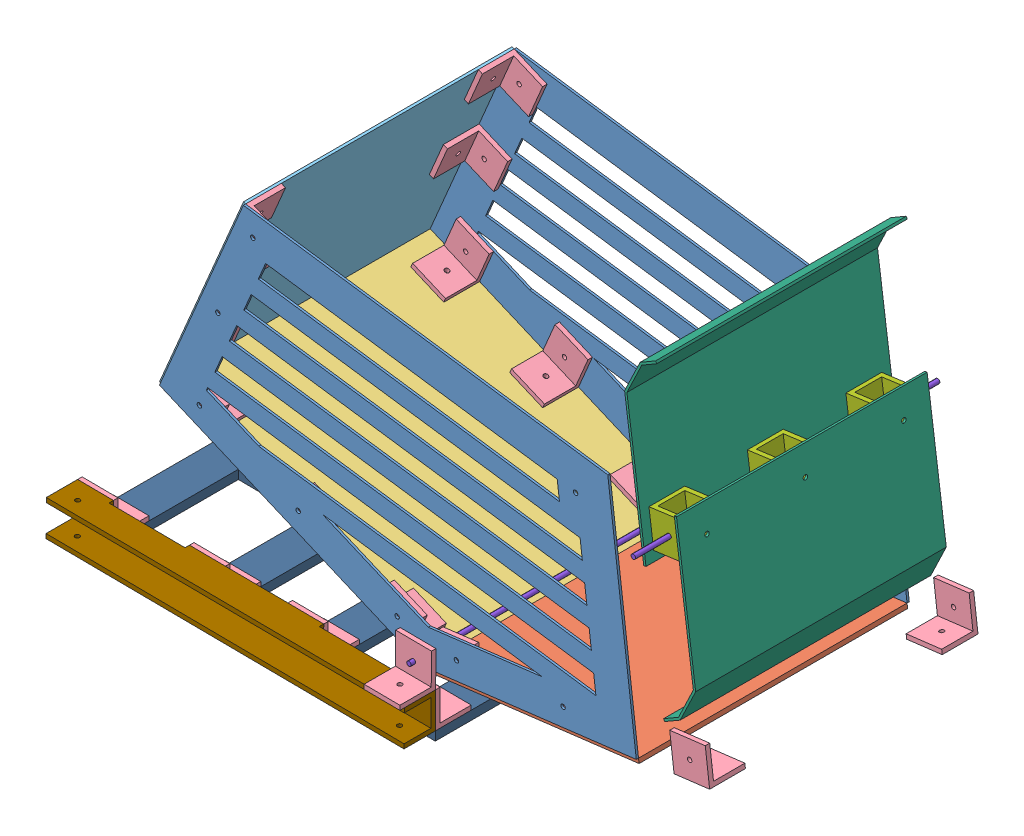
SolidWorks assembly total assem, configuration Default. Lengths in mm.
Overall size (442.28 299.16 254).
42 component instances, 11 part files, 72 mates.
Components (placement in the parent):
- 파트1-1: 파트1 [기본] at (16.2498 143.7805 409.1887) x (0.992546 0.121869 0) z (0 0 1) size (328.38 233.58 1.59)
- 파트1-2: 파트1 [기본] at (16.2498 143.7805 217.1012) x (0.992546 0.121869 0) z (0 0 1) size (328.38 233.58 1.59)
- 파트2-1: 파트2 [Default] at (117.4795 153.011 313.9387) x (0.992546 0.121869 0) z (0 0 1) size (152.4 3.17 190.5)
- 파트3-1: 파트3 [Default] at (-77.2734 183.4787 307.5887) x (-0.920505 0.390731 0) z (-0.390731 -0.920505 0) size (203.2 190.5 1.59)
- 파트5-2: 파트5 [Default] at (205.2455 166.9862 231.3887) x (0.992546 0.121869 0) z (-0.121869 0.992546 0) size (25.4 25.4 25.4)
- 파트5-3: 파트5 [Default] at (39.9128 159.4813 409.1887) x (0.992546 0.121869 0) z (0 0 -1) size (25.4 25.4 25.4)
- 파트5-5: 파트5 [Default] at (203.7942 179.5034 409.1887) x (0.992546 0.121869 0) z (0 0 -1) size (25.4 25.4 25.4)
- 파트5-6: 파트5 [Default] at (115.5448 168.7677 409.1887) x (0.992546 0.121869 0) z (0 0 -1) size (25.4 25.4 25.4)
- 파트5-7: 파트5 [Default] at (-2.1687 165.3954 409.1887) x (0.920505 -0.390731 0) z (0 0 -1) size (25.4 25.4 25.4)
- 파트5-8: 파트5 [Default] at (-72.3112 195.1691 409.1887) x (0.920505 -0.390731 0) z (0 0 -1) size (25.4 25.4 25.4)
- 파트5-10: 파트5 [Default] at (-72.3112 195.1691 218.6887) x (-0.920505 0.390731 0) z (0 0 1) size (25.4 25.4 25.4)
- 파트5-11: 파트5 [Default] at (-2.1687 165.3954 218.6887) x (-0.920505 0.390731 0) z (0 0 1) size (25.4 25.4 25.4)
- 파트5-12: 파트5 [Default] at (-142.4536 224.9429 218.6887) x (-0.920505 0.390731 0) z (0 0 1) size (25.4 25.4 25.4)
- 파트5-14: 파트5 [Default] at (39.9128 159.4813 218.6887) x (-0.992546 -0.121869 0) z (0 0 1) size (25.4 25.4 25.4)
- 파트5-15: 파트5 [Default] at (115.5448 168.7677 218.6887) x (-0.992546 -0.121869 0) z (0 0 1) size (25.4 25.4 25.4)
- 파트5-16: 파트5 [Default] at (-104.5212 346.8093 409.1887) x (-0.390731 -0.920505 0) z (0 0 -1) size (25.4 25.4 25.4)
- 파트5-17: 파트5 [Default] at (-142.4536 224.9429 409.1887) x (0.920505 -0.390731 0) z (0 0 -1) size (25.4 25.4 25.4)
- 파트5-18: 파트5 [Default] at (-129.3326 288.3572 409.1887) x (-0.390731 -0.920505 0) z (0 0 -1) size (25.4 25.4 25.4)
- 파트4-2: 파트4 [Default] at (-142.4843 293.9398 313.9387) x (-0.390731 -0.920505 0) z (0 0 1) size (152.4 1.59 190.5)
- 파트5-19: 파트5 [Default] at (-116.2116 351.7715 231.3887) x (-0.390731 -0.920505 0) z (0.920505 -0.390731 0) size (25.4 25.4 25.4)
- 파트5-20: 파트5 [Default] at (-141.023 293.3195 231.3887) x (-0.390731 -0.920505 0) z (0.920505 -0.390731 0) size (25.4 25.4 25.4)
- roller1-1: roller1 [Default] at (188.2429 345.4081 402.8387) x (0.991001 0.133852 0) z (0 0 -1) size (26.29 127.67 177.8)
- roller2-1: roller2 [Default] at (174.7933 309.5298 244.0887) x (0 0 1) z (0.991001 0.133852 0) size (25.4 25.4 25.4)
- roller3-1: roller3 [Default] at (17.3478 151.5925 205.9887) size (3.17 3.17 215.9)
- roller2-2: roller2 [Default] at (174.7933 309.5298 313.9387) x (0 0 1) z (0.991001 0.133852 0) size (25.4 25.4 25.4)
- roller2-5: roller2 [Default] at (174.7933 309.5298 383.7887) x (-0.991001 -0.133852 0) z (0 0 1) size (25.4 25.4 25.4)
- roller3-2: roller3 [Default] at (176.4933 296.9441 205.9887) size (3.17 3.17 215.9)
- LDO-2: LDO [Default] at (176.4933 296.9441 160.6199) x (0.973582 -0.228337 0) z (-0.228337 -0.973582 0) size (23.81 56.36 23.81) (hidden)
- roller1-2: roller1 [Default] at (164.7436 248.48 402.8387) x (-0.991001 -0.133852 0) z (0 0 -1) size (26.29 127.67 177.8)
- 파트5-21: 파트5 [Default] at (-62.2459 126.8861 212.3387) x (-0.999962 0.008727 0) z (0 0 1) size (25.4 25.4 25.4)
- 파트5-22: 파트5 [Default] at (17.3478 151.5925 415.5387) x (-0.999962 0.008727 0) z (0 0 1) size (25.4 25.4 25.4)
- 파트5-23: 파트5 [Default] at (-211.4652 128.1883 415.5387) x (0.999962 -0.008727 0) z (0 0 -1) size (25.4 25.4 25.4)
- 파트5-24: 파트5 [Default] at (17.1261 126.1935 212.3387) x (-0.999962 0.008727 0) z (0 0 1) size (25.4 25.4 25.4)
- 파트5-25: 파트5 [Default] at (-132.0932 127.4957 415.5387) x (0.999962 -0.008727 0) z (0 0 -1) size (25.4 25.4 25.4)
- 파트5-26: 파트5 [Default] at (-211.4652 128.1883 212.3387) x (-0.999962 0.008727 0) z (0 0 1) size (25.4 25.4 25.4)
- 파트7-1: 파트7 [Default] at (-224.1647 128.2992 201.2262) x (0 0 -1) z (0.999962 -0.008727 0) size (22.23 25.4 254)
- 파트6-1: 파트6 [Default] at (-97.3358 108.1416 313.9387) x (0 0 -1) z (0.008727 0.999962 0) size (203.2 254 6.35)
- 파트5-27: 파트5 [Default] at (-132.0932 127.4957 212.3387) x (-0.999962 0.008727 0) z (0 0 1) size (25.4 25.4 25.4)
- 파트7-2: 파트7 [Default] at (29.8256 126.0826 426.6512) x (0 0 1) z (-0.999962 0.008727 0) size (22.23 25.4 254)
- 파트5-28: 파트5 [Default] at (17.1261 126.1935 415.5387) x (0.999962 -0.008727 0) z (0 0 -1) size (25.4 25.4 25.4)
- 파트5-29: 파트5 [Default] at (-62.2459 126.8861 415.5387) x (0.999962 -0.008727 0) z (0 0 -1) size (25.4 25.4 25.4)
- 파트5-30: 파트5 [Default] at (17.3478 151.5925 212.3387) x (0.999962 -0.008727 0) z (0 0 -1) size (25.4 25.4 25.4)
Mates (geometry in assembly coordinates):
- 일치42: coincident aligned: circle of 파트3-1; circle of 파트5-10
- 일치43: coincident aligned: circle of 파트3-1; circle of 파트5-12
- 일치45: coincident aligned: circle of 파트4-2; circle of 파트5-20
- 일치46: coincident aligned: circle of 파트4-2; circle of 파트5-19
- 일치47: coincident anti-aligned: circle of 파트1-2; circle of 파트5-19
- 일치52: coincident aligned: cylinder of 파트1-2 through (-129.3326 288.3572 218.6887) axis (0 0 -1) radius 1.5875; circle of 파트5-20
- 일치57: coincident anti-aligned: plane of 파트1-2 through (16.2498 143.7805 218.6887) normal (0 0 1); plane of 파트5-2 through (217.4639 171.6853 218.6887) normal (0 0 -1)
- 일치58: coincident anti-aligned: plane of 파트2-1 through (117.0925 156.1624 313.9387) normal (-0.121869 0.992546 0); plane of 파트5-2 through (205.2455 166.9862 231.3887) normal (0.121869 -0.992546 0)
- 일치59: coincident anti-aligned: circle of 파트1-2; circle of 파트5-2
- 동심4: concentric aligned: cylinder of 파트1-1 through (17.3478 151.5925 410.7762) axis (0 0 -1) radius 1.7859; cylinder of roller3-1 through (17.3478 151.5925 421.8887) axis (0 0 -1) radius 1.5875
- 동심5: concentric anti-aligned: cylinder of roller3-2 through (176.4933 296.9441 421.8887) axis (0 0 -1) radius 1.5875; cylinder of LDO-2 through (176.4933 296.9441 214.5949) axis (0 0 1) radius 1.5875
- 거리1: distance = 0.125 mm anti-aligned: plane of LDO-2 through (176.4933 296.9441 216.9762) normal (0 0 1); plane of 파트1-2 through (16.2498 143.7805 217.1012) normal (0 0 -1)
- 동심6: concentric anti-aligned: cylinder of roller2-5 through (176.4933 296.9441 366.0087) axis (0 0 1) radius 1.5875; cylinder of roller3-2 through (176.4933 296.9441 421.8887) axis (0 0 -1) radius 1.5875
- 일치74: coincident aligned: circle of roller1-1; circle of roller2-5
- 동심7: concentric anti-aligned: cylinder of roller2-2 through (176.4933 296.9441 296.1587) axis (0 0 1) radius 1.5875; cylinder of roller3-2 through (176.4933 296.9441 421.8887) axis (0 0 -1) radius 1.5875
- 일치75: coincident anti-aligned: circle of roller1-1; cylinder of roller2-2 through (158.8732 294.5642 313.9387) axis (0.991001 0.133852 0) radius 1.5875
- 동심8: concentric anti-aligned: cylinder of roller2-1 through (176.4933 296.9441 226.3087) axis (0 0 1) radius 1.5875; cylinder of roller3-2 through (176.4933 296.9441 421.8887) axis (0 0 -1) radius 1.5875
- 동심9: concentric anti-aligned: cylinder of roller1-1 through (414.0486 329.0301 244.0887) axis (-0.991001 -0.133852 0) radius 1.5875; cylinder of roller2-1 through (158.8732 294.5642 244.0887) axis (0.991001 0.133852 0) radius 1.5875
- 너비2: width anti-aligned: plane of 파트1-1 through (16.2498 143.7805 409.1887) normal (0 0 -1); plane of roller2-5 through (16.2498 143.7805 218.6887) normal (0 0 1); plane of 파트1-2 through (165.6075 282.6584 396.4887) normal (0 0 1); plane of roller2-1 through (190.7789 286.0583 231.3887) normal (0 0 -1)
- 일치76: coincident aligned: circle of roller2-1; circle of roller1-2
- 일치77: coincident aligned: circle of roller2-2; circle of roller1-2
- 일치78: coincident anti-aligned: circle of roller2-5; circle of roller1-2
- 일치79: coincident anti-aligned: circle of 파트5-25; circle of 파트6-1
- 일치80: coincident anti-aligned: circle of 파트6-1; circle of 파트5-28
- 일치81: coincident anti-aligned: circle of 파트5-23; circle of 파트6-1
- 일치82: coincident anti-aligned: circle of 파트5-21; circle of 파트6-1
- 일치83: coincident anti-aligned: circle of 파트6-1; circle of 파트5-29
- 일치84: coincident aligned: circle of 파트7-2; circle of 파트5-28
- 일치85: coincident anti-aligned: circle of 파트5-24; circle of 파트6-1
- 일치86: coincident anti-aligned: circle of 파트6-1; circle of 파트5-27
- 일치87: coincident anti-aligned: circle of 파트5-26; circle of 파트6-1
- 일치88: coincident anti-aligned: circle of 파트5-22; circle of 파트7-2
- 일치89: coincident aligned: circle of 파트5-25; circle of 파트7-2
- 일치90: coincident aligned: plane of 파트5-22 through (30.1581 164.1812 418.7137) normal (0.999962 -0.008727 0); plane of 파트7-2 through (29.8256 126.0826 426.6512) normal (0.999962 -0.008727 0)
- 일치91: coincident aligned: plane of 파트5-28 through (17.1261 126.1935 412.3637) normal (0 0 -1); plane of 파트5-29 through (-62.2459 126.8861 412.3637) normal (0 0 -1)
- 일치92: coincident aligned: plane of 파트7-2 through (-224.0539 140.9987 437.7637) normal (0.008727 0.999962 0); plane of 파트5-28 through (29.9364 138.7821 412.3637) normal (0.008727 0.999962 0)
- 일치93: coincident anti-aligned: circle of 파트7-1; circle of 파트5-30
- 일치94: coincident aligned: plane of 파트5-23 through (-211.4652 128.1883 412.3637) normal (0 0 -1); plane of 파트5-25 through (-132.0932 127.4957 412.3637) normal (0 0 -1)
- 일치95: coincident aligned: circle of 파트5-24; circle of 파트7-1
- 일치96: coincident aligned: plane of 파트7-1 through (29.8256 126.0826 201.2262) normal (0.999962 -0.008727 0); plane of 파트5-30 through (30.1581 164.1812 209.1637) normal (0.999962 -0.008727 0)
- 일치97: coincident aligned: plane of 파트6-1 through (29.7148 113.3831 212.3387) normal (0.999962 -0.008727 0); plane of 파트5-28 through (29.9364 138.7821 412.3637) normal (0.999962 -0.008727 0)
- 일치98: coincident aligned: circle of 파트7-2; circle of 파트5-29
- 일치99: coincident aligned: circle of 파트7-1; circle of 파트5-27
- 일치100: coincident aligned: circle of 파트5-26; circle of 파트7-1
- 일치101: coincident aligned: circle of 파트5-21; circle of 파트7-1
- 일치102: coincident aligned: plane of 파트5-25 through (-132.0932 127.4957 412.3637) normal (0 0 -1); plane of 파트5-29 through (-62.2459 126.8861 412.3637) normal (0 0 -1)
- 동심10: concentric aligned: cylinder of roller3-1 through (17.3478 151.5925 421.8887) axis (0 0 -1) radius 1.5875; cylinder of 파트5-22 through (17.3478 151.5925 418.7137) axis (0 0 -1) radius 1.5875
- 일치103: coincident anti-aligned: circle of 파트1-1; circle of 파트5-5
- 일치104: coincident anti-aligned: circle of 파트2-1; circle of 파트5-5
- 일치105: coincident anti-aligned: circle of 파트2-1; circle of 파트5-6
- 일치107: coincident anti-aligned: circle of 파트1-1; circle of 파트5-6
- 일치108: coincident anti-aligned: circle of 파트2-1; circle of 파트5-3
- 일치109: coincident anti-aligned: circle of 파트1-1; circle of 파트5-3
- 일치110: coincident anti-aligned: circle of 파트1-1; circle of 파트5-7
- 일치111: coincident aligned: circle of 파트3-1; circle of 파트5-7
- 일치112: coincident aligned: circle of 파트3-1; circle of 파트5-8
- 일치114: coincident anti-aligned: circle of 파트1-1; circle of 파트5-8
- 일치115: coincident aligned: circle of 파트3-1; circle of 파트5-17
- 일치116: coincident anti-aligned: circle of 파트1-1; circle of 파트5-17
- 일치117: coincident anti-aligned: circle of 파트1-1; circle of 파트5-16
- 일치118: coincident anti-aligned: circle of 파트1-1; circle of 파트5-18
- 일치119: coincident anti-aligned: circle of 파트5-18; circle of 파트4-2
- 일치120: coincident anti-aligned: circle of 파트5-16; circle of 파트4-2
- 일치122: coincident aligned: circle of 파트1-2; circle of 파트5-11
- 일치123: coincident aligned: circle of 파트1-2; circle of 파트5-15
- 일치124: coincident anti-aligned: circle of 파트2-1; circle of 파트5-15
- 동심11: concentric aligned: cylinder of 파트1-1 through (175.2371 301.326 411.577) axis (0 0 -1) radius 1.7859; cylinder of roller3-2 through (175.2371 301.326 422.6895) axis (0 0 -1) radius 1.5875
- 너비3: width anti-aligned: plane of roller3-1 through (17.3478 151.5925 421.8887) normal (0 0 1); plane of 파트1-2 through (17.3478 151.5925 205.9887) normal (0 0 -1); plane of roller3-1 through (16.2498 143.7805 217.1012) normal (0 0 -1); plane of 파트1-1 through (16.2498 143.7805 410.7762) normal (0 0 1)
- 너비4: width anti-aligned: plane of roller3-2 through (176.4933 296.9441 421.8887) normal (0 0 1); plane of 파트1-2 through (176.4933 296.9441 205.9887) normal (0 0 -1); plane of roller3-2 through (16.2498 143.7805 217.1012) normal (0 0 -1); plane of 파트1-1 through (16.2498 143.7805 410.7762) normal (0 0 1)
- 동심12: concentric aligned: cylinder of roller3-1 through (17.3478 151.5925 421.8887) axis (0 0 -1) radius 1.5875; cylinder of 파트5-22 through (17.3478 151.5925 418.7137) axis (0 0 -1) radius 1.5875
- 너비5: width anti-aligned: plane of 파트1-1 through (16.2498 143.7805 410.7762) normal (0 0 1); plane of 파트5-22 through (16.2498 143.7805 217.1012) normal (0 0 -1); plane of 파트1-2 through (17.3478 151.5925 415.5387) normal (0 0 -1); plane of 파트5-30 through (17.3478 151.5925 212.3387) normal (0 0 1)
- 일치125: coincident anti-aligned: circle of 파트2-1; circle of 파트5-14
